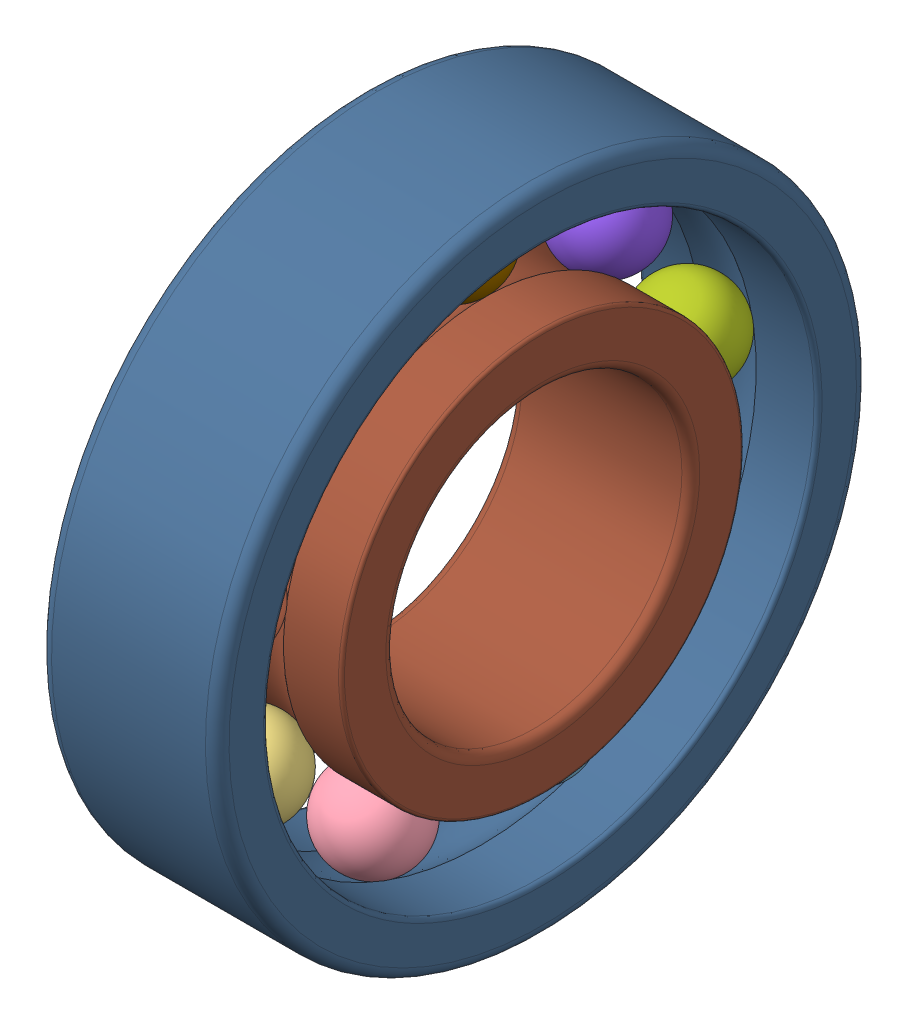
SolidWorks assembly 618_5_AUTOCAD_VERSION_2004_-_2006, configuration Défaut. Lengths in mm.
Overall size (3.01 11 11).
12 component instances, 12 part files, 0 mates.
Components (placement in the parent):
- 1_PART_618_5_PART1_in_ASM_618_5-1: 1_PART_618_5_PART1_in_ASM_618_5 [Défaut] at (1.5 3.0642 2.5712) size (1.96 2.07 2.07)
- 2_PART_618_5_PART2_in_ASM_618_5-1: 2_PART_618_5_PART2_in_ASM_618_5 [Défaut] at (1.5 0.6946 3.9392) size (2.15 2.2 2.14)
- 3_PART_618_5_PART3_in_ASM_618_5-1: 3_PART_618_5_PART3_in_ASM_618_5 [Défaut] at (1.5 -2 3.4641) size (1.97 2.11 2.11)
- 4_PART_618_5_PART3_in_ASM_618_5-1: 4_PART_618_5_PART3_in_ASM_618_5 [Défaut] at (1.5 -3.7588 1.3681) size (2.08 2.02 2.1)
- 5_PART_618_5_PART3_in_ASM_618_5-1: 5_PART_618_5_PART3_in_ASM_618_5 [Défaut] at (1.5 -3.7588 -1.3681) size (1.97 2.13 2.17)
- 6_PART_618_5_PART3_in_ASM_618_5-1: 6_PART_618_5_PART3_in_ASM_618_5 [Défaut] at (1.5 -2 -3.4641) size (2.07 2.2 2.04)
- 7_PART_618_5_PART3_in_ASM_618_5-1: 7_PART_618_5_PART3_in_ASM_618_5 [Défaut] at (1.5 0.6946 -3.9392) size (2.09 2.05 2.22)
- 8_PART_618_5_PART3_in_ASM_618_5-1: 8_PART_618_5_PART3_in_ASM_618_5 [Défaut] at (1.5 3.0642 -2.5712) size (2.02 2.17 2.18)
- 9_PART_618_5_PART3_in_ASM_618_5-1: 9_PART_618_5_PART3_in_ASM_618_5 [Défaut] at (1.5 4 0) size (2.21 2.22 2.24)
- 10_PART_618_5_PART3_in_ASM_618_5-1: 10_PART_618_5_PART3_in_ASM_618_5 [Défaut] at (1.5 0 0) size (3.01 11 11)
- 11_PART_618_5_PART3_in_ASM_618_5-1: 11_PART_618_5_PART3_in_ASM_618_5 [Défaut] at (1.5 0 0) size (3.01 6.8 6.8)
- 618_5_AUTOCAD_VERSION_2004_-_2006-1: 618_5_AUTOCAD_VERSION_2004_-_2006 [Défaut] at origin
